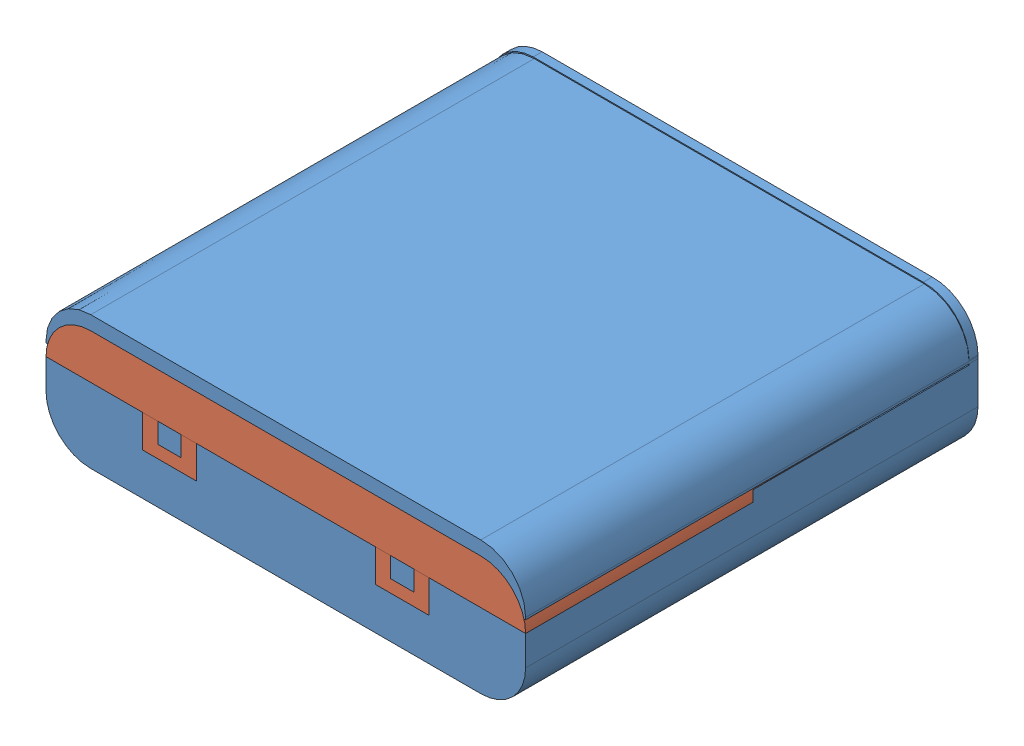
SolidWorks assembly BATTERY PACK, configuration Default. Lengths in mm.
Overall size (68.07 20.21 65.48).
3 component instances, 3 part files, 10 mates.
Components (placement in the parent):
- BATTERY PACK BASE-1: BATTERY PACK BASE [Default] at origin size (68.07 20.21 64.21)
- BATTERY PACK COVER-1: BATTERY PACK COVER [Default] at (0 -1.9812 0.635) size (68.07 10.97 65.48)
- Part2-1: Part2 [Default] at (0 0 -30.8356) size (14.8 14.8 48.68)
Mates (geometry in assembly coordinates):
- Coincident11: coincident: plane of BATTERY PACK BASE B-1 through (0 0 0) normal (0 0 1); plane of assembly through (0 0 0) normal (0 0 1)
- Coincident12: coincident: plane of BATTERY PACK BASE B-1 through (0 0 0) normal (0 1 0); plane of assembly through (0 0 0) normal (0 1 0)
- Coincident13: coincident aligned: plane of BATTERY PACK BASE B-1 through (0 0 0) normal (1 0 0); plane of assembly through (0 0 0) normal (1 0 0)
- Coincident15: coincident aligned: plane of BATTERY PACK COVER-1 through (0 -1.9812 0.635) normal (1 0 0); plane of assembly through (0 0 0) normal (1 0 0)
- Coincident16: coincident anti-aligned: plane of BATTERY PACK BASE B-1 through (0 10.5791 0) normal (0 1 0); plane of BATTERY PACK COVER-1 through (-34.036 10.5791 32.1056) normal (0 -1 0)
- Coincident17: coincident anti-aligned: plane of BATTERY PACK BASE B-1 through (34.036 18.9103 -30.8356) normal (0 0 1); plane of BATTERY PACK COVER-1 through (34.036 16.9291 -30.8356) normal (0 0 -1)
- InPlace1: in place: plane of BATTERY PACK BASE-1 through (34.036 18.9103 -30.8356) normal (0 0 1); plane of Part2-1 through (0 0 -30.8356) normal (0 0 1); moOrthogonalPlaneRef_w of BATTERY PACK BASE-1 through (34.036 18.9103 -30.8356) normal (0 0 1); plane of Part2-1 through (0 0 -30.8356) normal (0 1 0); plane of BATTERY PACK BASE-1 through (34.036 18.9103 -30.8356) normal (0 0 1); plane of Part2-1 through (0 0 -30.8356) normal (1 0 0); plane of BATTERY PACK BASE-1 through (34.036 18.9103 -30.8356) normal (0 0 1); unknown of Part2-1
- Coincident18: coincident aligned: plane of ?; plane of ?
- Coincident19: coincident aligned: moOrthogonalPlaneRef_w of BATTERY PACK BASE B-1 through (0 0 -30.8356) normal (0 1 0); plane of Part2^BATTERY PACK-1 through (0 0 -30.8356) normal (0 1 0)
- Coincident20: coincident anti-aligned: moOrthogonalPlaneRef_w of BATTERY PACK BASE B-1 through (0 0 -30.8356) normal (-1 0 0); plane of Part2^BATTERY PACK-1 through (0 0 -30.8356) normal (1 0 0)
